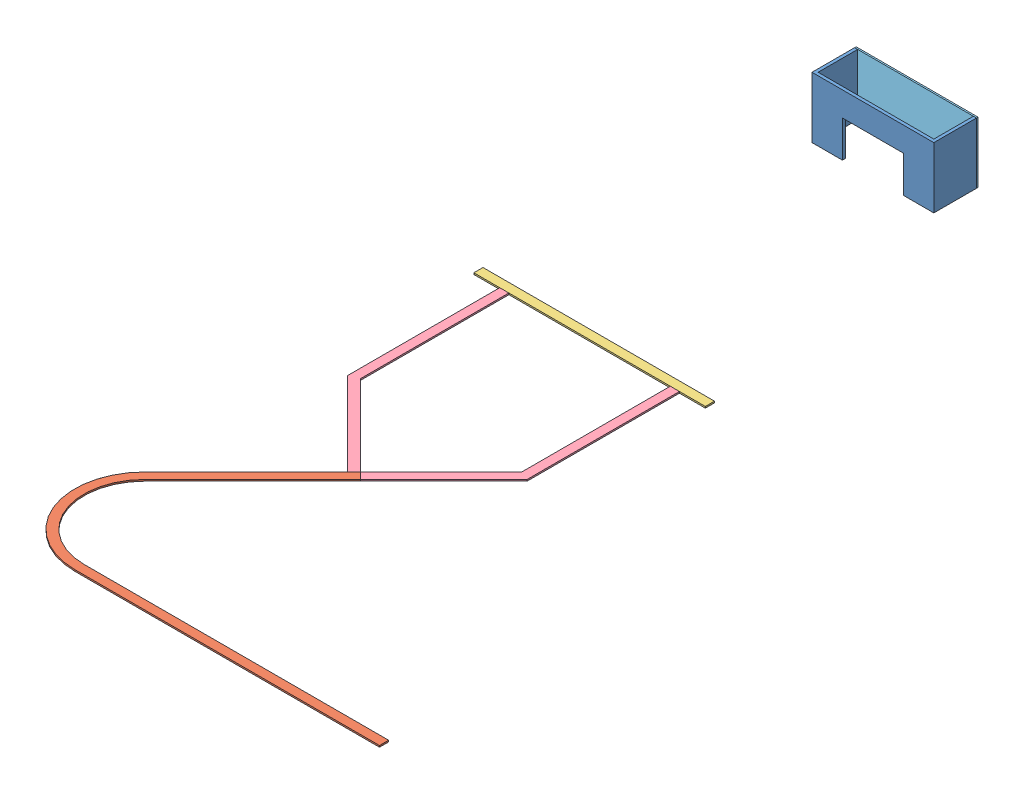
SolidWorks assembly goal, configuration Default. Lengths in mm.
Overall size (1230 200 2573.76).
6 component instances, 5 part files, 15 mates.
Components (placement in the parent):
- Goalpost-1: Goalpost [Default] at (150.7444 202.5088 310.5116) size (400 200 140)
- kick_path-1: kick_path [Default] at (359.8255 202.5088 2784.2731) x (0 0 1) z (-1 0 0) size (746.19 5 1230)
- Part8^goal-1: Part8^goal [Default] at (-165.4845 202.5088 209.9896) size (760 5 30) (virtual)
- red_line-3: red_line [Default] at (171.9576 202.5088 2089.2984) x (0 0 1) z (-1 0 0) size (773.79 5 295)
- red_line-4: red_line [Default] at (129.5312 207.5088 2089.2984) x (0 0 1) z (1 0 0) size (773.79 5 295)
- Part1^goal-1: Part1^goal [Default] at (0 0 240.5116) size (400 200 5) (virtual)
Mates (geometry in assembly coordinates):
- Distance2: distance = 900 mm anti-aligned: plane of Part8^goal-1 through (-229.2556 207.5088 1285.5116) normal (0 0 -1); plane of Goalpost-1 through (-49.2556 402.5088 385.5116) normal (0 0 1)
- Distance3: distance = 180 mm aligned: plane of Goalpost-1 through (-49.2556 402.5088 235.5116) normal (-1 0 0); plane of Part8^goal-1 through (-229.2556 207.5088 1285.5116) normal (-1 0 0)
- Coincident37: coincident anti-aligned: plane of Part8^goal-1 through (-229.2556 207.5088 1315.5116) normal (0 0 1); plane of red_line-3 through (445.7444 207.5088 1315.5116) normal (0 0 -1)
- Coincident38: coincident aligned: plane of Part8^goal-1 through (-165.4845 207.5088 209.9896) normal (0 1 0); plane of red_line-3 through (171.9576 207.5088 2089.2984) normal (0 1 0)
- Coincident40: coincident anti-aligned: plane of red_line-3 through (415.7444 207.5088 1803.0852) normal (-0.707107 0 -0.707107); plane of red_line-4 through (150.7444 202.5088 2068.0852) normal (0.707107 0 0.707107)
- Coincident41: coincident anti-aligned: plane of Part8^goal-1 through (-229.2556 207.5088 1315.5116) normal (0 0 1); plane of red_line-4 through (-144.2556 202.5088 1315.5116) normal (0 0 -1)
- Coincident42: coincident: point of red_line-3; point of red_line-4
- Coincident43: coincident anti-aligned: plane of kick_path-1 through (171.9576 207.5088 2089.2984) normal (0.707107 0 -0.707107); plane of red_line-3 through (150.7444 207.5088 2068.0852) normal (-0.707107 0 0.707107)
- Coincident44: coincident anti-aligned: plane of kick_path-1 through (150.7444 207.5088 2068.0852) normal (-0.707107 0 -0.707107); plane of red_line-4 through (150.7444 202.5088 2068.0852) normal (0.707107 0 0.707107)
- Coincident45: coincident aligned: plane of kick_path-1 through (-40.1745 207.5088 2584.2731) normal (0 1 0); plane of red_line-3 through (171.9576 207.5088 2089.2984) normal (0 1 0)
- Distance4: distance = 85 mm aligned: plane of Part8^goal-1 through (-229.2556 207.5088 1285.5116) normal (-1 0 0); plane of red_line-4 through (-144.2556 202.5088 1815.5116) normal (-1 0 0)
- Coincident47: coincident aligned: plane of Goalpost-1 through (150.7444 202.5088 310.5116) normal (0 -1 0); plane of Part8^goal-1 through (-165.4845 202.5088 209.9896) normal (0 -1 0)
- Coincident48: coincident: plane of Goalpost-1 through (150.7444 202.5088 245.5116) normal (0 0 -1); plane of Part1^goal-1 through (0 0 245.5116) normal (0 0 1)
- Coincident49: coincident: plane of Goalpost-1 through (150.7444 402.5088 310.5116) normal (0 1 0); plane of Part1^goal-1 through (350.7444 402.5088 245.5116) normal (0 1 0)
- Coincident50: coincident aligned: plane of Goalpost-1 through (350.7444 402.5088 235.5116) normal (1 0 0); plane of Part1^goal-1 through (350.7444 402.5088 245.5116) normal (1 0 0)
